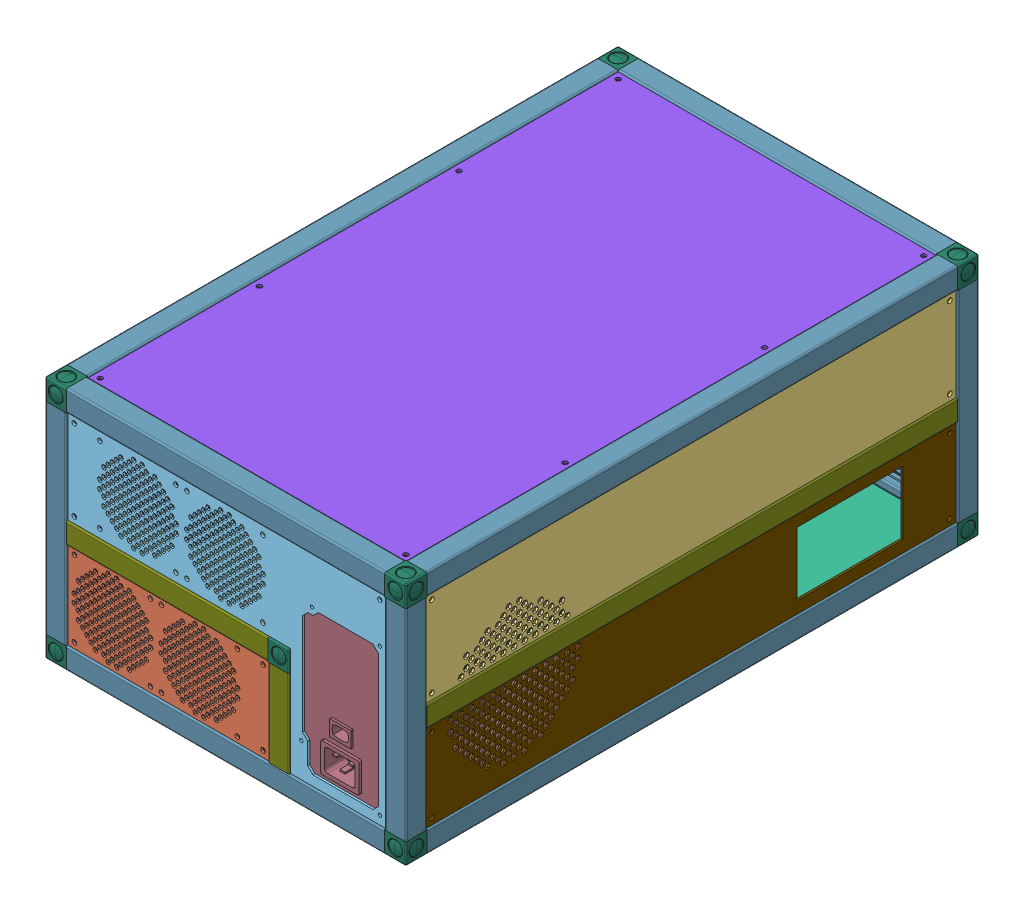
SolidWorks assembly LaserBox, configuration Default. Lengths in mm.
Overall size (341 231 541).
99 component instances, 32 part files, 59 mates.
Components (placement in the parent):
- BI020-A - FBC-4-1: BI020-A - FBC-4 [Default] at (60 10 53.5) x (0 0 1) z (-1 0 0) size (107 39 67)
- BI014-A - MBL-FN-473-1: BI014-A - MBL-FN-473 [Default] at (65 107 259.2894) x (0 0 1) z (-1 0 0) size (232.49 92.5 115)
- BI012-A - MDL-III-405-1: BI012-A - MDL-III-405 [Default] at (-54.9408 149.5 354) x (0 0 1) z (-1 0 0) size (193.1 46 73)
- BI015-A - OEM-MD-640-1: BI015-A - OEM-MD-640 [Default] at (42.9796 107 107.5) size (212.52 95 80)
- BI013-A - OEM-N-532-1: BI013-A - OEM-N-532 [Default] at (-54.9408 107 178.5) x (0 0 1) z (-1 0 0) size (279.11 50.5 70)
- BI017-A - OEM-PSU-405-1: BI017-A - OEM-PSU-405 [Default] at (62.5 5 347.5) x (-1 0 0) z (0 0 -1) size (109.25 57.86 62)
- BI019-A - OEM-PSU-473-1: BI019-A - OEM-PSU-473 [Default] at (115 5 212.5) x (0 0 1) z (-1 0 0) size (60 73.93 148.97)
- BI018-A - OEM-PSU-532-1: BI018-A - OEM-PSU-532 [Default] at (-32.5882 5 110) x (-1 0 0) z (0 0 -1) size (100 60 246.25)
- BI016-A - OEM-PSU-640-1: BI016-A - OEM-PSU-640 [Default] at (58.5 4.2076 432.5) size (120.61 66.34 79.65)
- PP016-A - FBC-4 Mount Bottom-1: PP016-A - FBC-4 Mount Bottom [Default] at (60 5 53.5) x (0 0 -1) z (1 0 0) size (90 43.5 60)
- PP017-A - FBC-4 Mount Top-1: PP017-A - FBC-4 Mount Top [Default] at (60 49 53.5) x (0 0 -1) z (1 0 0) size (90 5.19 60)
- PP013-A - Optical Cable Guide-1: PP013-A - Optical Cable Guide [Default] at (-11.0367 107 65.1026) x (-1 0 0) z (0 0 -1) size (106 32 106)
- BI009-A - Corsair AX1600i-1: BI009-A - Corsair AX1600i [Default] at (166.75 80 416.5) x (0 0 -1) z (0 -1 0) size (202.5 86.5 150)
- Skeleton-1: Skeleton [Default] at (230 -17 -20) size (341 231 541)
  - BI010-A - BoschProfile 2NVS-20: BI010-A - BoschProfile 2NVS [L=300] at (-20 10 10) x (0 -1 0) z (-1 0 0) size (20 20 300)
  - BI010-A - BoschProfile 2NVS-21: BI010-A - BoschProfile 2NVS [L=300] at (-20 10 530) x (0 0 1) z (-1 0 0) size (20 20 300)
  - BI010-A - BoschProfile 2NVS-22: BI010-A - BoschProfile 2NVS [L=500] at (-10 10 20) size (20 20 500)
  - BI010-A - BoschProfile 2NVS-23: BI010-A - BoschProfile 2NVS [L=500] at (-330 10 520) x (-1 0 0) z (0 0 -1) size (20 20 500)
  - BI010-A - BoschProfile 2NVS-17: BI010-A - BoschProfile 2NVS [L=200] at (-330 -790 530) x (0 0 1) z (0 1 0) size (20 20 190)
  - BI010-A - BoschProfile 2NVS-19: BI010-A - BoschProfile 2NVS [L=200] at (-10 -790 10) x (0 0 -1) z (0 1 0) size (20 20 190)
  - BI010-A - BoschProfile 2NVS-18: BI010-A - BoschProfile 2NVS [L=200] at (-330 -790 10) x (-1 0 0) z (0 1 0) size (20 20 190)
  - BI007-A - Cubic Connector 20x20-12: BI007-A - Cubic Connector 20x20 [Default] at (-20 10 10) x (-1 0 0) z (0 0 -1) size (33 33 33)
  - BI007-A - Cubic Connector 20x20-13: BI007-A - Cubic Connector 20x20 [Default] at (-330 10 20) x (0 0 1) z (-1 0 0) size (33 33 33)
  - BI010-A - BoschProfile 2NVS-13: BI010-A - BoschProfile 2NVS [L=200] at (-10 -790 530) x (1 0 0) z (0 1 0) size (20 20 190)
  - BI007-A - Cubic Connector 20x20-7: BI007-A - Cubic Connector 20x20 [Default] at (-10 10 520) x (0 0 -1) z (1 0 0) size (33 33 33)
  - BI007-A - Cubic Connector 20x20-8: BI007-A - Cubic Connector 20x20 [Default] at (-320 10 530) size (33 33 33)
  - BI007-A - Cubic Connector 20x20-9: BI007-A - Cubic Connector 20x20 [Default] at (-10 220 520) x (0 0 -1) z (0 1 0) size (33 33 33)
  - BI007-A - Cubic Connector 20x20-6: BI007-A - Cubic Connector 20x20 [Default] at (-320 220 530) x (1 0 0) z (0 1 0) size (33 33 33)
  - BI007-A - Cubic Connector 20x20-10: BI007-A - Cubic Connector 20x20 [Default] at (-330 220 20) x (0 0 1) z (0 1 0) size (33 33 33)
  - BI007-A - Cubic Connector 20x20-11: BI007-A - Cubic Connector 20x20 [Default] at (-20 220 10) x (-1 0 0) z (0 1 0) size (33 33 33)
  - BI010-A - BoschProfile 2NVS-15: BI010-A - BoschProfile 2NVS [L=500] at (-10 220 20) x (0 1 0) z (0 0 1) size (20 20 500)
  - BI010-A - BoschProfile 2NVS-14: BI010-A - BoschProfile 2NVS [L=500] at (-330 220 520) x (0 1 0) z (0 0 -1) size (20 20 500)
  - BI010-A - BoschProfile 2NVS-12: BI010-A - BoschProfile 2NVS [L=300] at (-20 220 10) x (0 0 -1) z (-1 0 0) size (20 20 300)
  - BI010-A - BoschProfile 2NVS-16: BI010-A - BoschProfile 2NVS [L=300] at (-20 220 530) x (0 1 0) z (-1 0 0) size (20 20 300)
  - BI011-A - BoschProfile 3N-7: BI011-A - BoschProfile 3N [L = 300] at (-20 112 10) x (0 0 -1) z (-1 0 0) size (20 20 300)
  - BI011-A - BoschProfile 3N-18: BI011-A - BoschProfile 3N [L = 500] at (-330 112 520) x (-1 0 0) z (0 0 -1) size (20 20 500)
  - BI011-A - BoschProfile 3N-19: BI011-A - BoschProfile 3N [L = 82] at (-120 102 530) x (0 0 1) z (0 -1 0) size (20 20 82)
  - BI011-A - BoschProfile 3N-20: BI011-A - BoschProfile 3N [L = 500] at (-120 112 520) x (0 1 0) z (0 0 -1) size (20 20 500)
  - BI011-A - BoschProfile 3N-16: BI011-A - BoschProfile 3N [L = 180] at (-130 112 530) x (0 0 1) z (-1 0 0) size (20 20 190)
  - BI007-A - Cubic Connector 20x20-14: BI007-A - Cubic Connector 20x20 [Default] at (-120 102 530) x (0 -1 0) z (1 0 0) size (33 33 33)
  - BI011-A - BoschProfile 3N-17: BI011-A - BoschProfile 3N [L = 500] at (-10 112 520) x (1 0 0) z (0 0 -1) size (20 20 500)
  - BI008-A - Bracket-S 20X20-21: BI008-A - Bracket-S 20X20 [Default] at (-320 122 530) x (0 0 -1) z (0 1 0) size (15.51 28.51 28.51)
  - BI008-A - Bracket-S 20X20-22: BI008-A - Bracket-S 20X20 [Default] at (-130 20 530) x (0 0 -1) z (-1 0 0) size (15.51 28.51 28.51)
  - BI008-A - Bracket-S 20X20-25: BI008-A - Bracket-S 20X20 [Default] at (-330 102 520) x (1 0 0) z (0 -1 0) size (15.51 28.51 28.51)
  - BI008-A - Bracket-S 20X20-20: BI008-A - Bracket-S 20X20 [Default] at (-330 102 20) size (15.51 28.51 28.51)
  - BI008-A - Bracket-S 20X20-23: BI008-A - Bracket-S 20X20 [Default] at (-10 102 20) x (-1 0 0) z (0 -1 0) size (15.51 28.51 28.51)
  - BI008-A - Bracket-S 20X20-24: BI008-A - Bracket-S 20X20 [Default] at (-10 102 520) x (-1 0 0) z (0 0 -1) size (15.51 28.51 28.51)
  - BI008-A - Bracket-S 20X20-18: BI008-A - Bracket-S 20X20 [Default] at (-20 102 10) x (0 0 1) z (-1 0 0) size (15.51 28.51 28.51)
  - BI008-A - Bracket-S 20X20-17: BI008-A - Bracket-S 20X20 [Default] at (-320 102 10) x (0 0 1) z (0 -1 0) size (15.51 28.51 28.51)
  - BI008-A - Bracket-S 20X20-15: BI008-A - Bracket-S 20X20 [Default] at (-130 112 20) x (0 1 0) z (-1 0 0) size (15.51 28.51 28.51)
  - BI011-A - BoschProfile 3N-15: BI011-A - BoschProfile 3N [L = 300] at (-20 10 330) x (0 -1 0) z (-1 0 0) size (20 20 300)
  - BI008-A - Bracket-S 20X20-16: BI008-A - Bracket-S 20X20 [Default] at (-320 10 340) x (0 1 0) z (0 0 1) size (15.51 28.51 28.51)
  - BI008-A - Bracket-S 20X20-19: BI008-A - Bracket-S 20X20 [Default] at (-20 10 340) x (0 1 0) z (-1 0 0) size (15.51 28.51 28.51)
  - CR020-A - PanelLaserBox1-1: CR020-A - PanelLaserBox1 [Default] at (-338.5 102 20) x (0 0 1) z (0 1 0) size (500 2 82)
  - CR020-A - PanelLaserBox1-2: CR020-A - PanelLaserBox1 [FanSide] at (-1.5 102 520) x (0 0 -1) z (0 1 0) size (500 2 82)
  - CR021-A - PanelLaserBox2-1: CR021-A - PanelLaserBox2 [Default] at (-320 20 1.5) x (1 0 0) z (0 -1 0) size (300 2 82)
  - CR022-A - PanelLaserBox3-1: CR022-A - PanelLaserBox3 [Default] at (-320 20 536.5) x (1 0 0) z (0 -1 0) size (190 2 82)
  - CR023-A - PanelLaserBox4-1: CR023-A - PanelLaserBox4 [FanSide] at (-3.5 210 20) x (0 0 1) z (0 1 0) size (500 2 88)
  - CR023-A - PanelLaserBox4-2: CR023-A - PanelLaserBox4 [Default] at (-336.5 210 520) x (0 0 -1) z (0 1 0) size (500 2 88)
  - CR024-A - PanelLaserBox5-1: CR024-A - PanelLaserBox5 [Default] at (-320 210 3.5) x (1 0 0) z (0 1 0) size (300 2 88)
  - CR025-A - PanelLaserBox6-1: CR025-A - PanelLaserBox6 [Default] at (-110 122 536.5) x (1 0 0) z (0 -1 0) size (300 2 190)
  - CR026-A - PanelLaserBox7-2: CR026-A - PanelLaserBox7 [Default] at (-170 22 270) x (0 0 -1) z (1 0 0) size (530 2 330)
  - CR027-A - PanelLaserBox8-2: CR027-A - PanelLaserBox8 [Default] at (-170 124 270) x (0 0 -1) z (1 0 0) size (530 2 330)
  - CR028-A - PanelLaserBox9-2: CR028-A - PanelLaserBox9 [Default] at (-170 228.5 270) x (0 0 -1) z (1 0 0) size (500 2 300)
  - PP010-A - Plate Holder-57: PP010-A - Plate Holder [Default] at (-330 15.4 13.4) x (1 0 0) z (0 -1 0) size (12.3 11.8 14.6)
  - PP010-A - Plate Holder-59: PP010-A - Plate Holder [Default] at (-330 15.4 501.6) x (1 0 0) z (0 -1 0) size (12.3 11.8 14.6)
  - PP010-A - Plate Holder-58: PP010-A - Plate Holder [Default] at (-13.4 15.4 10) x (0 0 1) z (0 -1 0) size (12.3 11.8 14.6)
  - PP010-A - Plate Holder-60: PP010-A - Plate Holder [Default] at (-10 15.4 526.6) x (-1 0 0) z (0 -1 0) size (12.3 11.8 14.6)
  - PP010-A - Plate Holder-63: PP010-A - Plate Holder [Default] at (-330 117.4 13.4) x (1 0 0) z (0 -1 0) size (12.3 11.8 14.6)
  - PP010-A - Plate Holder-61: PP010-A - Plate Holder [Default] at (-13.4 117.4 10) x (0 0 1) z (0 -1 0) size (12.3 11.8 14.6)
  - PP010-A - Plate Holder-62: PP010-A - Plate Holder [Default] at (-10 117.4 526.6) x (-1 0 0) z (0 -1 0) size (12.3 11.8 14.6)
  - PP010-A - Plate Holder-73: PP010-A - Plate Holder [Default] at (-15.4 220 526.6) x (0 -1 0) z (1 0 0) size (12.3 11.8 14.6)
  - PP010-A - Plate Holder-74: PP010-A - Plate Holder [Default] at (-324.6 220 13.4) x (0 -1 0) z (-1 0 0) size (12.3 11.8 14.6)
  - PP010-A - Plate Holder-68: PP010-A - Plate Holder [Default] at (-326.6 214.6 10) x (0 0 1) z (0 1 0) size (12.3 11.8 14.6)
  - PP010-A - Plate Holder-75: PP010-A - Plate Holder [Default] at (-13.4 214.6 530) x (0 0 -1) z (0 1 0) size (12.3 11.8 14.6)
  - PP010-A - Plate Holder-67: PP010-A - Plate Holder [Default] at (-330 214.6 526.6) x (1 0 0) z (0 1 0) size (12.3 11.8 14.6)
  - PP010-A - Plate Holder-69: PP010-A - Plate Holder [Default] at (-10 214.6 13.4) x (-1 0 0) z (0 1 0) size (12.3 11.8 14.6)
  - PP010-A - Plate Holder-64: PP010-A - Plate Holder [Default] at (-123.4 106.6 530) x (0 0 -1) z (0 1 0) size (12.3 11.8 14.6)
  - PP010-A - Plate Holder-65: PP010-A - Plate Holder [Default] at (-301.6 15.4 10) x (0 0 1) z (0 -1 0) size (12.3 11.8 14.6)
  - PP010-A - Plate Holder-72: PP010-A - Plate Holder [Default] at (-301.6 117.4 10) x (0 0 1) z (0 -1 0) size (12.3 11.8 14.6)
  - PP010-A - Plate Holder-70: PP010-A - Plate Holder [Default] at (-38.4 214.6 10) x (0 0 1) z (0 1 0) size (12.3 11.8 14.6)
  - PP010-A - Plate Holder-71: PP010-A - Plate Holder [Default] at (-10 15.4 38.4) x (-1 0 0) z (0 -1 0) size (12.3 11.8 14.6)
  - PP010-A - Plate Holder-66: PP010-A - Plate Holder [Default] at (-10 117.4 38.4) x (-1 0 0) z (0 -1 0) size (12.3 11.8 14.6)
  - PP010-A - Plate Holder-41: PP010-A - Plate Holder [Default] at (-10 214.6 501.6) x (-1 0 0) z (0 1 0) size (12.3 11.8 14.6)
  - PP010-A - Plate Holder-43: PP010-A - Plate Holder [Default] at (-301.6 214.6 530) x (0 0 -1) z (0 1 0) size (12.3 11.8 14.6)
  - PP010-A - Plate Holder-54: PP010-A - Plate Holder [Default] at (-330 117.4 501.6) x (1 0 0) z (0 -1 0) size (12.3 11.8 14.6)
  - PP010-A - Plate Holder-55: PP010-A - Plate Holder [Default] at (-330 214.6 38.4) x (1 0 0) z (0 1 0) size (12.3 11.8 14.6)
  - PP010-A - Plate Holder-56: PP010-A - Plate Holder [Default] at (-324.6 220 501.6) x (0 -1 0) z (-1 0 0) size (12.3 11.8 14.6)
  - PP010-A - Plate Holder-53: PP010-A - Plate Holder [Default] at (-15.4 220 38.4) x (0 -1 0) z (1 0 0) size (12.3 11.8 14.6)
  - PP011-A - PSU Fan Guide Top-1: PP011-A - PSU Fan Guide Top [Default] at (-16.5 97 436.5) x (0 0 -1) z (0 -1 0) size (142.7 16 46)
  - PP012-A - PSU Fan Guide Bottom-1: PP012-A - PSU Fan Guide Bottom [Default] at (-16.5 102 436.5) x (0 0 -1) z (0 -1 0) size (148.33 16.5 75.99)
- PP018-A - OEM PSU Mount-4: PP018-A - OEM PSU Mount [Default] at (3 4.2076 432.5) x (0 0 1) z (-1 0 0) size (62 20 9)
- PP018-A - OEM PSU Mount-5: PP018-A - OEM PSU Mount [Default] at (114 4.2076 432.5) x (0 0 -1) z (1 0 0) size (62 20 9)
- PP018-A - OEM PSU Mount-3: PP018-A - OEM PSU Mount [Default] at (11 5 347.5) x (0 0 1) z (-1 0 0) size (62 20 9)
- PP018-A - OEM PSU Mount-6: PP018-A - OEM PSU Mount [Default] at (114 5 347.5) x (0 0 -1) z (1 0 0) size (62 20 9)
- PP018-A - OEM PSU Mount-7: PP018-A - OEM PSU Mount [Default] at (186.5 5 212.5) x (0 0 -1) z (1 0 0) size (62 20 9)
- PP018-A - OEM PSU Mount-8: PP018-A - OEM PSU Mount [Default] at (43.5 5 212.5) x (0 0 1) z (-1 0 0) size (62 20 9)
- PP014-A - Spacer Laser Left-1: PP014-A - Spacer Laser Left [Default] at (-84.6908 107 412) x (0 0 -1) z (1 0 0) size (115 42.5 15)
- PP015-A - Spacer Laser Right-2: PP015-A - Spacer Laser Right [Default] at (-25.1908 107 412) x (0 0 1) z (-1 0 0) size (115 42.5 15)
Mates (geometry in assembly coordinates):
- Symmetric1: symmetric: plane of BI020-A - FBC-4-1 through (80 49 16.5) normal (1 0 0); plane of assembly; plane of BI020-A - FBC-4-1 through (40 49 16.5) normal (-1 0 0)
- Coincident3: coincident: plane of BI020-A - FBC-4-1 through (60 28 0) normal (0 0 -1); plane of assembly through (0 0 0) normal (0 0 1)
- Width1: width: plane of PP016-A - FBC-4 Mount Bottom-1 through (80.5 30 13) normal (0 0 1); plane of PP016-A - FBC-4 Mount Bottom-1 through (80.5 30 94) normal (0 0 -1); plane of BI020-A - FBC-4-1 through (43 49 13.5) normal (0 0 -1); plane of BI020-A - FBC-4-1 through (43 49 93.5) normal (0 0 1)
- Width2: width: plane of PP016-A - FBC-4 Mount Bottom-1 through (39.5 30 94) normal (1 0 0); plane of PP016-A - FBC-4 Mount Bottom-1 through (80.5 30 94) normal (-1 0 0); plane of BI020-A - FBC-4-1 through (40 49 16.5) normal (-1 0 0); plane of BI020-A - FBC-4-1 through (80 49 16.5) normal (1 0 0)
- Coincident4: coincident: plane of BI020-A - FBC-4-1 through (43 10 90.5) normal (0 -1 0); plane of PP016-A - FBC-4 Mount Bottom-1 through (60 10 53.5) normal (0 1 0)
- Width3: width: plane of PP017-A - FBC-4 Mount Top-1 through (41.435 54 10) normal (0 0 -1); plane of PP017-A - FBC-4 Mount Top-1 through (78.565 54 97) normal (0 0 1); plane of PP016-A - FBC-4 Mount Bottom-1 through (83.5 30 97) normal (0 0 1); plane of PP016-A - FBC-4 Mount Bottom-1 through (83.5 30 10) normal (0 0 -1)
- Width4: width: plane of PP017-A - FBC-4 Mount Top-1 through (83.5 54 8.5) normal (1 0 0); plane of PP017-A - FBC-4 Mount Top-1 through (36.5 54 28.7) normal (-1 0 0); plane of PP016-A - FBC-4 Mount Bottom-1 through (36.5 30 97) normal (-1 0 0); plane of PP016-A - FBC-4 Mount Bottom-1 through (83.5 30 97) normal (1 0 0)
- Coincident5: coincident: plane of BI020-A - FBC-4-1 through (43 49 90.5) normal (0 1 0); plane of PP017-A - FBC-4 Mount Top-1 through (60 49 53.5) normal (0 -1 0)
- Coincident86: coincident: plane of BI009-A - Corsair AX1600i-1 through (210 16 341.5) normal (1 0 0); plane of Skeleton-1/BI010-A - BoschProfile 2NVS-22 through (210 1.5 1000) normal (-1 0 0)
- Distance28: distance = 2 mm: plane of Skeleton-1/BI010-A - BoschProfile 2NVS-22 through (216.5 3 1000) normal (0 1 0); plane of BI009-A - Corsair AX1600i-1 through (199.25 5 509) normal (0 -1 0)
- Coincident87: coincident: plane of BI020-A - FBC-4-1 through (60 28 0) normal (0 0 -1); plane of Skeleton-1/BI010-A - BoschProfile 2NVS-20 through (-790 -3.5 0) normal (0 0 1)
- Coincident88: coincident: plane of BI009-A - Corsair AX1600i-1 through (209.25 5.75 516.5) normal (0 0 1); plane of Skeleton-1/CR025-A - PanelLaserBox6-1 through (120 105 516.5) normal (0 0 -1)
- Coincident95: coincident: plane of BI018-A - OEM-PSU-532-1 through (-82.5882 5 160) normal (0 -1 0); plane of Skeleton-1/CR026-A - PanelLaserBox7-2 through (60 5 250) normal (0 1 0)
- Coincident96: coincident: plane of BI019-A - OEM-PSU-473-1 through (45 5 242.5) normal (0 -1 0); plane of Skeleton-1/CR026-A - PanelLaserBox7-2 through (60 5 250) normal (0 1 0)
- Coincident97: coincident: plane of BI013-A - OEM-N-532-1 through (-54.9408 107 178.5) normal (0 -1 0); plane of Skeleton-1/CR027-A - PanelLaserBox8-2 through (60 107 250) normal (0 1 0)
- Distance31: distance = 165 mm: plane of BI013-A - OEM-N-532-1 through (-89.9408 118 350) normal (0 0 1); plane of Skeleton-1/CR027-A - PanelLaserBox8-2 through (-75 105 515) normal (0 0 1)
- Width10: width: plane of BI012-A - MDL-III-405-1 through (-91.4408 159.5 354) normal (-1 0 0); plane of BI012-A - MDL-III-405-1 through (-18.4408 159.5 354) normal (1 0 0); plane of BI013-A - OEM-N-532-1 through (-89.9408 118 178.5) normal (-1 0 0); plane of BI013-A - OEM-N-532-1 through (-19.9408 118 178.5) normal (1 0 0)
- Coincident98: coincident: plane of BI014-A - MBL-FN-473-1 through (65 107 259.2894) normal (0 -1 0); plane of Skeleton-1/CR027-A - PanelLaserBox8-2 through (60 107 250) normal (0 1 0)
- Coincident99: coincident: plane of BI014-A - MBL-FN-473-1 through (122.5 110 269.2894) normal (1 0 0); plane of Skeleton-1/CR027-A - PanelLaserBox8-2 through (122.5 104.999 515) normal (1 0 0)
- Distance32: distance = 45 mm: plane of BI012-A - MDL-III-405-1 through (-32.4408 195.5 470) normal (0 0 1); plane of Skeleton-1/CR027-A - PanelLaserBox8-2 through (-75 105 515) normal (0 0 1)
- Coincident100: coincident: plane of BI015-A - OEM-MD-640-1 through (42.9796 107 107.5) normal (0 -1 0); plane of Skeleton-1/CR027-A - PanelLaserBox8-2 through (60 107 250) normal (0 1 0)
- Distance33: distance = 42.5 mm: plane of BI015-A - OEM-MD-640-1 through (167.4796 202 27.5) normal (0 0 -1); plane of Skeleton-1/CR027-A - PanelLaserBox8-2 through (195 105 -15) normal (0 0 -1)
- Coincident101: coincident: plane of PP013-A - Optical Cable Guide-1 through (-11.0367 107 65.1026) normal (0 -1 0); plane of Skeleton-1/CR027-A - PanelLaserBox8-2 through (60 107 250) normal (0 1 0)
- Parallel1: parallel: plane of BI019-A - OEM-PSU-473-1 through (115 5 182.5) normal (0 0 -1); plane of Skeleton-1/BI010-A - BoschProfile 2NVS-12 through (-790 211.5 -20) normal (0 0 -1)
- Coincident102: coincident: line of BI017-A - OEM-PSU-405-1 through (13.5 5 378.5) axis (0 0 -1); plane of Skeleton-1/CR026-A - PanelLaserBox7-2 through (60 5 250) normal (0 1 0)
- Coincident103: coincident: line of BI017-A - OEM-PSU-405-1 through (111.4823 5 378.5) axis (0 0 -1); plane of Skeleton-1/CR026-A - PanelLaserBox7-2 through (60 5 250) normal (0 1 0)
- Parallel3: parallel: plane of BI017-A - OEM-PSU-405-1 through (62.5 5 316.5) normal (0 0 -1); plane of Skeleton-1/BI010-A - BoschProfile 2NVS-12 through (-790 211.5 -20) normal (0 0 -1)
- Width11: width: plane of BI018-A - OEM-PSU-532-1 through (-82.5882 4.999 173) normal (0 0 1); plane of BI018-A - OEM-PSU-532-1 through (-82.5882 4.999 177) normal (0 0 -1); cylinder of Skeleton-1/CR026-A - PanelLaserBox7-2 through (-77.5 5 175) axis (0 1 0) radius 1.6
- Width12: width: plane of BI018-A - OEM-PSU-532-1 through (17.4118 4.999 243) normal (0 0 1); plane of BI018-A - OEM-PSU-532-1 through (17.4118 4.999 247) normal (0 0 -1); cylinder of Skeleton-1/CR026-A - PanelLaserBox7-2 through (12.5 5 245) axis (0 1 0) radius 1.6
- Concentric1: concentric: cylinder of BI016-A - OEM-PSU-640-1 through (4.5 19.2076 404.375) axis (-1 0 0) radius 1.25; cylinder of PP018-A - OEM PSU Mount-4 through (1.5 19.2076 404.375) axis (-1 0 0) radius 1.7
- Concentric2: concentric: cylinder of BI016-A - OEM-PSU-640-1 through (4.5 19.2076 460.625) axis (-1 0 0) radius 1.25; cylinder of PP018-A - OEM PSU Mount-4 through (1.5 19.2076 460.625) axis (-1 0 0) radius 1.7
- Coincident104: coincident: plane of BI016-A - OEM-PSU-640-1 through (4.5 44.2076 463.625) normal (-1 0 0); plane of PP018-A - OEM PSU Mount-4 through (4.5 24.2076 401.5) normal (1 0 0)
- Coincident105: coincident: plane of BI016-A - OEM-PSU-640-1 through (112.5 44.2076 463.625) normal (1 0 0); plane of PP018-A - OEM PSU Mount-5 through (112.5 24.2076 463.5) normal (-1 0 0)
- Concentric3: concentric: cylinder of BI016-A - OEM-PSU-640-1 through (112.5 19.2076 404.375) axis (1 0 0) radius 1.25; cylinder of PP018-A - OEM PSU Mount-5 through (115.5 19.2076 404.375) axis (1 0 0) radius 1.7
- Concentric4: concentric: cylinder of BI016-A - OEM-PSU-640-1 through (112.5 19.2076 460.625) axis (1 0 0) radius 1.25; cylinder of PP018-A - OEM PSU Mount-5 through (115.5 19.2076 460.625) axis (1 0 0) radius 1.7
- Coincident106: coincident: plane of BI017-A - OEM-PSU-405-1 through (12.5 38 316.5) normal (-1 0 0); plane of PP018-A - OEM PSU Mount-3 through (12.5 25 316.5) normal (1 0 0)
- Concentric5: concentric: cylinder of BI017-A - OEM-PSU-405-1 through (28.6378 10 368.5) axis (-1 0 0) radius 1.5; cylinder of PP018-A - OEM PSU Mount-3 through (9.5 10 368.5) axis (-1 0 0) radius 1.7
- Concentric6: concentric: cylinder of BI017-A - OEM-PSU-405-1 through (28.6378 10 326.5) axis (-1 0 0) radius 1.5; cylinder of PP018-A - OEM PSU Mount-3 through (9.5 10 326.5) axis (-1 0 0) radius 1.7
- Coincident108: coincident: plane of BI017-A - OEM-PSU-405-1 through (112.5 38 316.5) normal (1 0 0); plane of PP018-A - OEM PSU Mount-6 through (112.5 25 378.5) normal (-1 0 0)
- Concentric7: concentric: cylinder of BI017-A - OEM-PSU-405-1 through (96.3622 10 368.5) axis (1 0 0) radius 1.5; cylinder of PP018-A - OEM PSU Mount-6 through (115.5 10 368.5) axis (1 0 0) radius 1.7
- Concentric8: concentric: cylinder of BI017-A - OEM-PSU-405-1 through (96.3622 10 326.5) axis (1 0 0) radius 1.5; cylinder of PP018-A - OEM PSU Mount-6 through (115.5 10 326.5) axis (1 0 0) radius 1.7
- Coincident109: coincident: plane of BI019-A - OEM-PSU-473-1 through (185 49 242.5) normal (1 0 0); plane of PP018-A - OEM PSU Mount-7 through (185 25 243.5) normal (-1 0 0)
- Concentric9: concentric: cylinder of BI019-A - OEM-PSU-473-1 through (185 12.5 239.5) axis (1 0 0) radius 1.25; cylinder of PP018-A - OEM PSU Mount-7 through (188 12.5 239.5) axis (1 0 0) radius 1.7
- Concentric10: concentric: cylinder of BI019-A - OEM-PSU-473-1 through (185 12.5 185.5) axis (1 0 0) radius 1.25; cylinder of PP018-A - OEM PSU Mount-7 through (188 12.5 185.5) axis (1 0 0) radius 1.7
- Coincident110: coincident: plane of BI019-A - OEM-PSU-473-1 through (45 49 242.5) normal (-1 0 0); plane of PP018-A - OEM PSU Mount-8 through (45 25 181.5) normal (1 0 0)
- Concentric11: concentric: cylinder of BI019-A - OEM-PSU-473-1 through (45 12.5 185.5) axis (-1 0 0) radius 1.25; cylinder of PP018-A - OEM PSU Mount-8 through (42 12.5 185.5) axis (-1 0 0) radius 1.7
- Concentric12: concentric: cylinder of BI019-A - OEM-PSU-473-1 through (45 12.5 239.5) axis (-1 0 0) radius 1.25; cylinder of PP018-A - OEM PSU Mount-8 through (42 12.5 239.5) axis (-1 0 0) radius 1.7
- Concentric13: concentric: cylinder of Skeleton-1/CR026-A - PanelLaserBox7-2 through (7.5 5 335) axis (0 1 0) radius 1.6; cylinder of PP018-A - OEM PSU Mount-3 through (7.5 10 335) axis (0 1 0) radius 1.6
- Concentric14: concentric: circle of Skeleton-1/CR026-A - PanelLaserBox7-2; circle of PP018-A - OEM PSU Mount-5
- Concentric15: concentric: cylinder of Skeleton-1/CR026-A - PanelLaserBox7-2 through (-0.5 5 445) axis (0 1 0) radius 1.6; cylinder of PP018-A - OEM PSU Mount-4 through (-0.5 9.2076 445) axis (0 1 0) radius 1.6
- Concentric16: concentric: cylinder of Skeleton-1/CR026-A - PanelLaserBox7-2 through (40 5 200) axis (0 1 0) radius 1.6; cylinder of PP018-A - OEM PSU Mount-8 through (40 10 200) axis (0 1 0) radius 1.6
- Concentric17: concentric: cylinder of Skeleton-1/CR026-A - PanelLaserBox7-2 through (190 5 225) axis (0 1 0) radius 1.6; cylinder of PP018-A - OEM PSU Mount-7 through (190 10 225) axis (0 1 0) radius 1.6
- Width13: width: plane of PP014-A - Spacer Laser Left-1 through (-92.1908 149.5 469.5) normal (-1 0 0); plane of PP014-A - Spacer Laser Left-1 through (-77.1908 149.5 469.5) normal (1 0 0); plane of BI012-A - MDL-III-405-1 through (-81.4408 149.499 447.5) normal (-1 0 0); plane of BI012-A - MDL-III-405-1 through (-87.9408 149.499 447.5) normal (1 0 0)
- Coincident111: coincident: plane of Skeleton-1/CR027-A - PanelLaserBox8-2 through (60 107 250) normal (0 1 0); plane of PP014-A - Spacer Laser Left-1 through (-84.6908 107 412) normal (0 -1 0)
- Width14: width: plane of BI012-A - MDL-III-405-1 through (-18.4408 159.5 354) normal (0 0 -1); plane of BI012-A - MDL-III-405-1 through (-18.4408 159.5 470) normal (0 0 1); plane of PP014-A - Spacer Laser Left-1 through (-77.1908 149.5 469.5) normal (0 0 1); plane of PP014-A - Spacer Laser Left-1 through (-77.1908 149.5 354.5) normal (0 0 -1)
- Coincident112: coincident: plane of BI012-A - MDL-III-405-1 through (-54.9408 149.5 354) normal (0 -1 0); plane of PP014-A - Spacer Laser Left-1 through (-84.6908 149.5 412) normal (0 1 0)
- Width16: width: plane of PP015-A - Spacer Laser Right-2 through (-17.6908 149.5 354.5) normal (1 0 0); plane of PP015-A - Spacer Laser Right-2 through (-32.6908 149.5 354.5) normal (-1 0 0); plane of BI012-A - MDL-III-405-1 through (-28.4408 149.499 367.5) normal (1 0 0); plane of BI012-A - MDL-III-405-1 through (-21.9408 149.499 367.5) normal (-1 0 0)
- Coincident113: coincident: plane of BI012-A - MDL-III-405-1 through (-54.9408 149.5 354) normal (0 -1 0); plane of PP015-A - Spacer Laser Right-2 through (-25.1908 149.5 412) normal (0 1 0)
- Coincident114: coincident: plane of PP014-A - Spacer Laser Left-1 through (-77.1908 149.5 469.5) normal (0 0 1); plane of PP015-A - Spacer Laser Right-2 through (-32.6908 149.5 469.5) normal (0 0 1)
